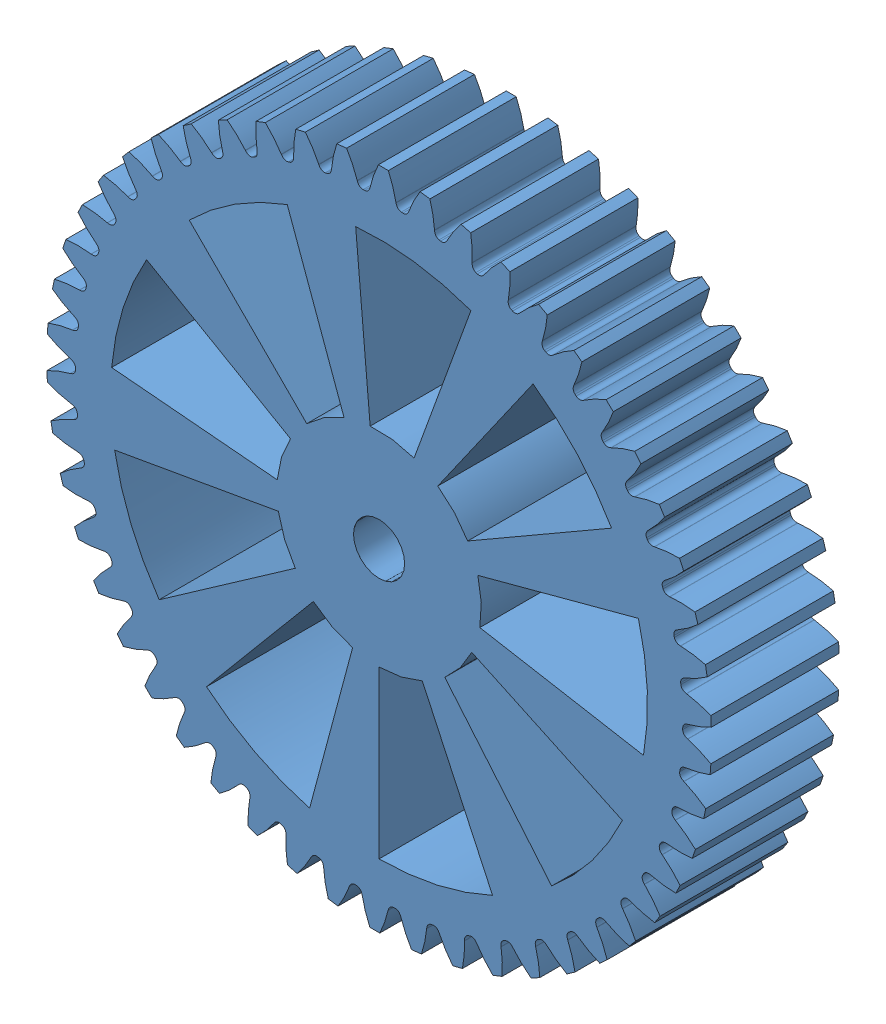
SolidWorks assembly 10-50t gear, configuration Default. Lengths in mm.
Overall size (25.98 26 11).
3 component instances, 3 part files, 2 mates.
Components (placement in the parent):
- 10t 2mm bore-1: 10t 2mm bore [Gear Blank] at (3.2172 4.5415 3.1315) size (5.79 6 6) (hidden)
- 50t 2mm bore-1: 50t 2mm bore [Gear Blank] at (3.2172 4.5415 9.1315) x (-0.965291 0.261177 0) z (0 0 1) size (25.97 26 5) (hidden)
- 10-50t dual gear-1: 10-50t dual gear [Default] at origin size (25.98 26 11)
Mates (geometry in assembly coordinates):
- Concentric1: concentric aligned: cylinder of 10t 2mm bore-1 through (3.2172 4.5415 9.1315) axis (0 0 -1) radius 1; cylinder of 50t 2mm bore-1 through (3.2172 4.5415 14.1315) axis (0 0 -1) radius 1
- Coincident2: coincident anti-aligned: plane of 10t 2mm bore-1 through (2.943 7.3317 9.1315) normal (0 0 1); plane of 50t 2mm bore-1 through (0.1798 -7.8399 9.1315) normal (0 0 -1)
